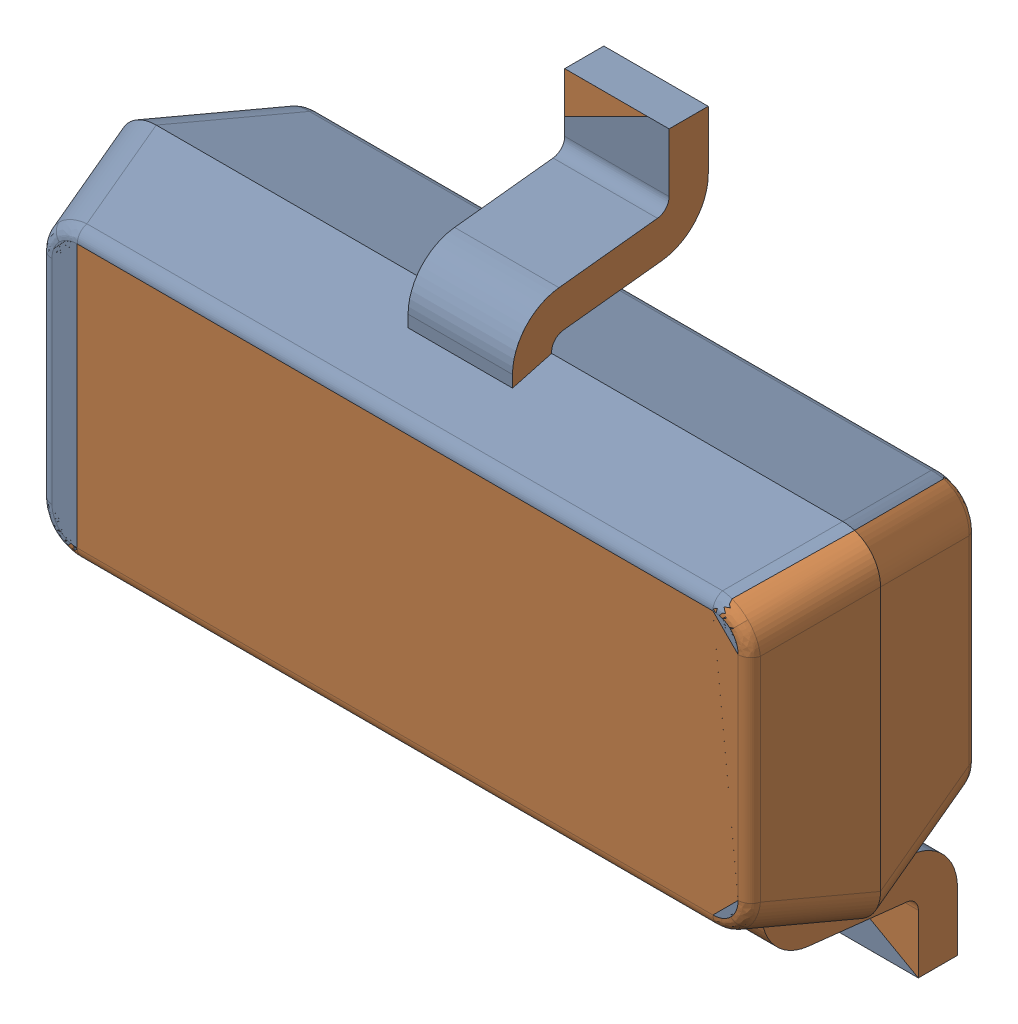
SolidWorks assembly BAT1, configuration Default. Lengths in mm.
Overall size (2.92 2.34 1).
2 component instances, 1 part files, 0 mates.
Components (placement in the parent):
- User_Library-BAT54-1: User_Library-BAT54 [Default] at (34.9999 26.7499 0) x (1 0 0) z (0 0 1) size (2.92 2.34 1)
- User_Library-BAT54-2: User_Library-BAT54 [Default] at (35 26.7499 0) x (1 0 0) z (0 0 1) size (2.92 2.34 1)
